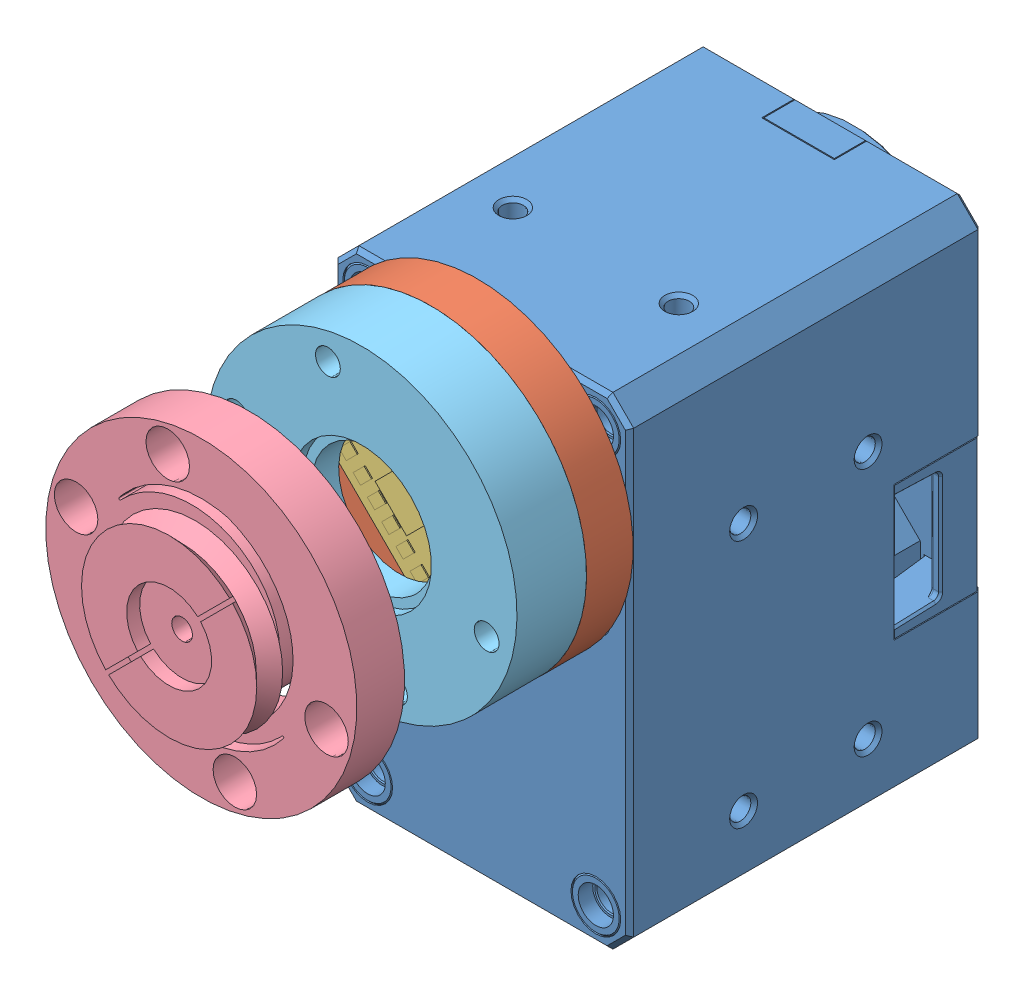
SolidWorks assembly SEA_v3, configuration 기본. Lengths in mm.
Overall size (42.43 56.46 66.14).
5 component instances, 5 part files, 13 mates.
Components (placement in the parent):
- xm-430_idle(stp)-1: xm-430_idle(stp) [기본] at (-0.2851 10.5461 44.3001) size (28.5 46.5 42.4)
- SEA_motor_v5-1: SEA_motor_v5 [기본] at (-0.2851 10.5461 61.7001) size (30 30 4.5)
- encoder-2: encoder [기본] at (-0.2851 10.5461 66.2001) x (0.707107 -0.707107 0) z (0 0 1) size (13 13 2.1)
- SEA_pulley_v7_part2-1: SEA_pulley_v7_part2 [기본] at (-0.2851 10.5461 83.7432) x (-0.707107 0.707107 0) z (0 0 1) size (30 30 10.9)
- SEA_pulley_v5_part1-1: SEA_pulley_v5_part1 [기본] at (-0.2851 10.5461 66.2001) x (0.707107 -0.707107 0) z (0 0 1) size (30 30 6.7)
Mates (geometry in assembly coordinates):
- 동심1: concentric anti-aligned: cylinder of xm-430_idle(stp)-1 through (-0.2851 10.5461 65.2001) axis (0 0 1) radius 2.25; cylinder of SEA_motor_v5-1 through (-0.2851 10.5461 66.2001) axis (0 0 -1) radius 4.2
- 동심2: concentric anti-aligned: cylinder of xm-430_idle(stp)-1 through (-0.2851 18.5461 60.6954) axis (0 0 1) radius 0.8; cylinder of SEA_motor_v5-1 through (-0.2851 18.5461 66.2001) axis (0 0 -1) radius 1.1
- 일치3: coincident anti-aligned: plane of xm-430_idle(stp)-1 through (-0.2851 10.5461 63.3001) normal (0 0 1); plane of SEA_motor_v5-1 through (-0.2851 10.5461 63.3001) normal (0 0 -1)
- 일치4: coincident anti-aligned: plane of SEA_motor_v5-1 through (-0.2851 10.5461 66.2001) normal (0 0 1); plane of encoder-2 through (-0.2851 10.5461 66.2001) normal (0 0 -1)
- 동심6: concentric aligned: cylinder of SEA_motor_v5-1 through (-0.2851 10.5461 66.2001) axis (0 0 -1) radius 15; cylinder of SEA_pulley_v7_part2-1 through (-0.2851 10.5461 88.3432) axis (0 0 -1) radius 15
- 동심7: concentric aligned: cylinder of SEA_motor_v5-1 through (-0.2851 10.5461 66.2001) axis (0 0 -1) radius 15; cylinder of SEA_pulley_v5_part1-1 through (-0.2851 10.5461 69.2001) axis (0 0 -1) radius 15
- 동심9: concentric anti-aligned: cylinder of SEA_motor_v5-1 through (-3.5203 22.6202 66.2001) axis (0 0 -1) radius 1; cylinder of SEA_pulley_v5_part1-1 through (-3.5203 22.6202 66.2001) axis (0 0 1) radius 1.2
- 동심10: concentric aligned: cylinder of SEA_pulley_v7_part2-1 through (-3.5203 22.6202 83.7432) axis (0 0 1) radius 1.2; cylinder of SEA_pulley_v5_part1-1 through (-3.5203 22.6202 66.2001) axis (0 0 1) radius 1.2
- 일치5: coincident anti-aligned: plane of SEA_motor_v5-1 through (-0.2851 10.5461 66.2001) normal (0 0 1); plane of SEA_pulley_v5_part1-1 through (-0.2851 10.5461 66.2001) normal (0 0 -1)
- 일치6: coincident anti-aligned: plane of SEA_pulley_v7_part2-1 through (-0.2851 10.5461 72.8001) normal (0 0 -1); plane of SEA_pulley_v5_part1-1 through (-0.2851 10.5461 72.8001) normal (0 0 1)
- 동심12: concentric aligned: cylinder of SEA_motor_v5-1 through (-4.2449 14.5059 64.2001) axis (0 0 1) radius 1; cylinder of encoder-2 through (-4.2449 14.5059 63.3717) axis (0 0 1) radius 1
- 동심15: concentric aligned: cylinder of SEA_motor_v5-1 through (3.6747 6.5863 64.2001) axis (0 0 1) radius 1; cylinder of encoder-2 through (3.6747 6.5863 63.3717) axis (0 0 1) radius 1
- 일치9: coincident anti-aligned: plane of SEA_motor_v5-1 through (-0.2851 10.5461 66.2001) normal (0 0 1); plane of SEA_pulley_v5_part1-1 through (-0.2851 10.5461 66.2001) normal (0 0 -1)
